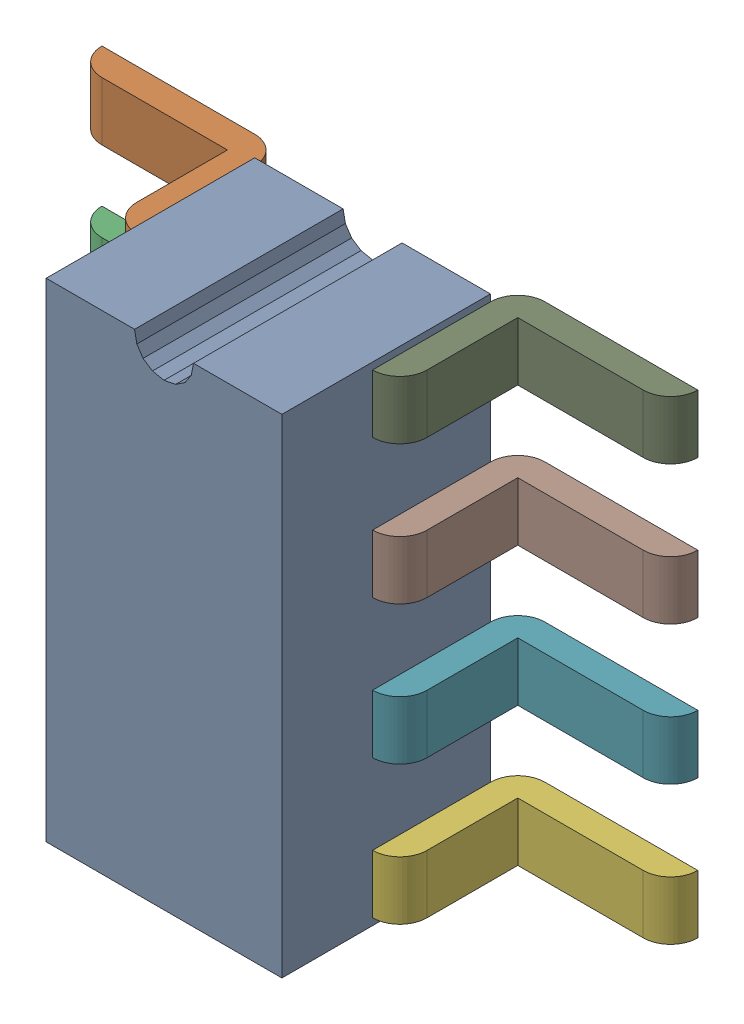
SolidWorks assembly U2, configuration Défaut. Lengths in mm.
Overall size (5.46 4.47 2.16).
10 component instances, 9 part files, 0 mates.
Components (placement in the parent):
- Open CASCADE STEP translator 6.8 1.16.1-1: Open CASCADE STEP translator 6.8 1.16.1 [Défaut] at origin size (5.46 4.47 2.16)
  - Body_1_9-1: Body_1_9 [Défaut] at origin size (2.16 4.47 1.91)
  - Pin_1_6-1: Pin_1_6 [Défaut] at origin size (1.65 0.54 1.33)
  - Pin_2_6-1: Pin_2_6 [Défaut] at origin size (1.65 0.54 1.33)
  - Pin_3_4-1: Pin_3_4 [Défaut] at origin size (1.65 0.54 1.33)
  - Pin_4_3-1: Pin_4_3 [Défaut] at origin size (1.65 0.54 1.33)
  - Pin_5_3-1: Pin_5_3 [Défaut] at (5.207 -3.81 0) x (-1 0 0) z (0 0 1) size (1.65 0.54 1.33)
  - Pin_6_3-1: Pin_6_3 [Défaut] at (5.207 -1.27 0) x (-1 0 0) z (0 0 1) size (1.65 0.54 1.33)
  - Pin_7-1: Pin_7 [Défaut] at (5.207 1.27 0) x (-1 0 0) z (0 0 1) size (1.65 0.54 1.33)
  - Pin_8-1: Pin_8 [Défaut] at (5.207 3.81 0) x (-1 0 0) z (0 0 1) size (1.65 0.54 1.33)
